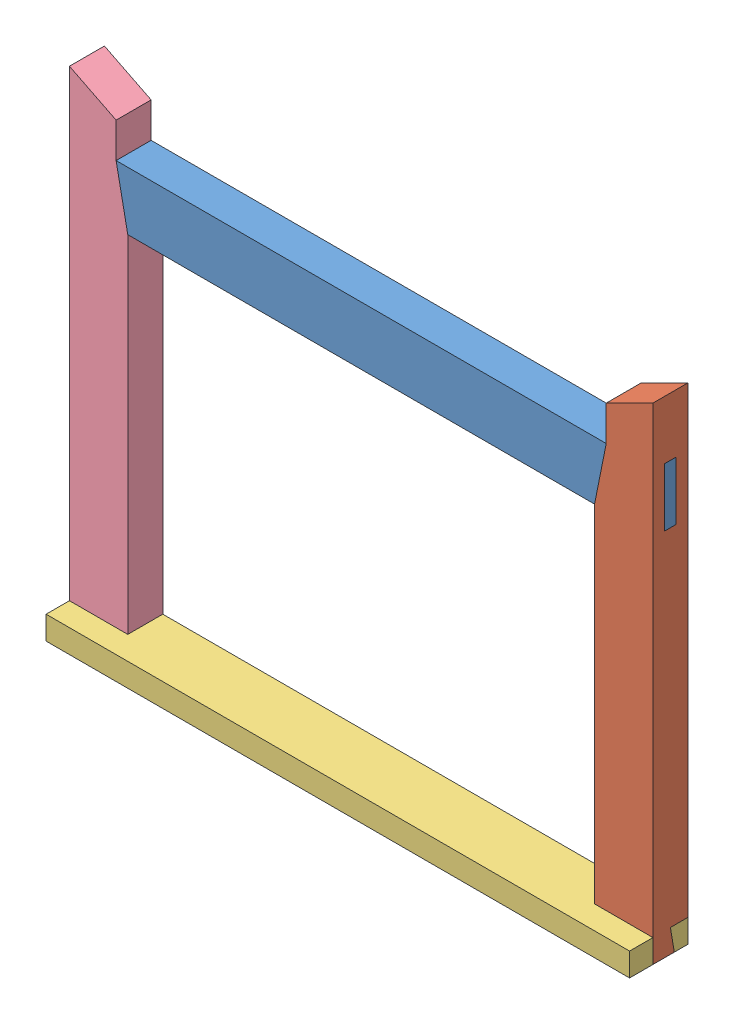
SolidWorks assembly Assembly Frame, configuration Default. Lengths in mm.
Overall size (300 250 30).
5 component instances, 5 part files, 11 mates.
Components (placement in the parent):
- Side Rails-1: Side Rails [Default] at (-73.6241 1.4898 37.8383) (suppressed, hidden)
- Top Rail-1: Top Rail [Default] at (61.3759 81.4898 37.8383) size (300 30 18)
- Right Rail-1: Right Rail [Default] at (196.3759 1.4898 37.8383) size (30 250 18)
- Bottom Rail-1: Bottom Rail [Default] at (61.3759 -117.5102 43.8383) size (300 12 30)
- Left Rails-1: Left Rails [Default] at (-73.6241 1.4898 37.8383) size (30 250 18)
Mates (geometry in assembly coordinates):
- Coincident1: coincident anti-aligned: plane of Side Rails-1 through (-58.6241 66.4898 46.8383) normal (0.980581 0.196116 0); plane of Top Rail-1 through (-64.6241 96.4898 40.8383) normal (-0.980581 -0.196116 0)
- Coincident2: coincident aligned: line of Side Rails-1 through (-58.6241 66.4898 46.8383) axis (-0.196116 0.980581 0); line of Top Rail-1 through (-58.6241 66.4898 46.8383) axis (-0.196116 0.980581 0)
- Coincident3: coincident anti-aligned: plane of Side Rails-1 through (-88.6241 66.4898 40.8383) normal (0 1 0); plane of Top Rail-1 through (211.3759 66.4898 46.8383) normal (0 -1 0)
- Coincident7: coincident anti-aligned: plane of Top Rail-1 through (187.3759 96.4898 40.8383) normal (0.980581 -0.196116 0); plane of Right Rail-1 through (181.3759 66.4898 46.8383) normal (-0.980581 0.196116 0)
- Coincident8: coincident anti-aligned: plane of Top Rail-1 through (211.3759 96.4898 40.8383) normal (0 0 1); plane of Right Rail-1 through (211.3759 96.4898 40.8383) normal (0 0 -1)
- Coincident12: coincident anti-aligned: line of Top Rail-1 through (187.3759 96.4898 40.8383) axis (0 0 1); line of Right Rail-1 through (187.3759 96.4898 46.8383) axis (0 0 -1)
- Coincident16: coincident aligned: plane of Right Rail-1 through (211.3759 -123.5102 46.8383) normal (0 -1 0); plane of Bottom Rail-1 through (-88.6241 -123.5102 28.8383) normal (0 -1 0)
- Coincident17: coincident aligned: plane of Right Rail-1 through (211.3759 -123.5102 46.8383) normal (1 0 0); plane of Bottom Rail-1 through (211.3759 -111.5102 58.8383) normal (1 0 0)
- Coincident18: coincident anti-aligned: plane of Top Rail-1 through (-64.6241 96.4898 34.8383) normal (-0.980581 -0.196116 0); plane of Left Rails-1 through (-58.6241 66.4898 46.8383) normal (0.980581 0.196116 0)
- Coincident19: coincident anti-aligned: plane of Top Rail-1 through (-88.6241 96.4898 40.8383) normal (0 0 1); plane of Left Rails-1 through (-88.6241 96.4898 40.8383) normal (0 0 -1)
- Coincident20: coincident aligned: plane of Top Rail-1 through (-88.6241 66.4898 46.8383) normal (-1 0 0); plane of Left Rails-1 through (-88.6241 -123.5102 46.8383) normal (-1 0 0)
